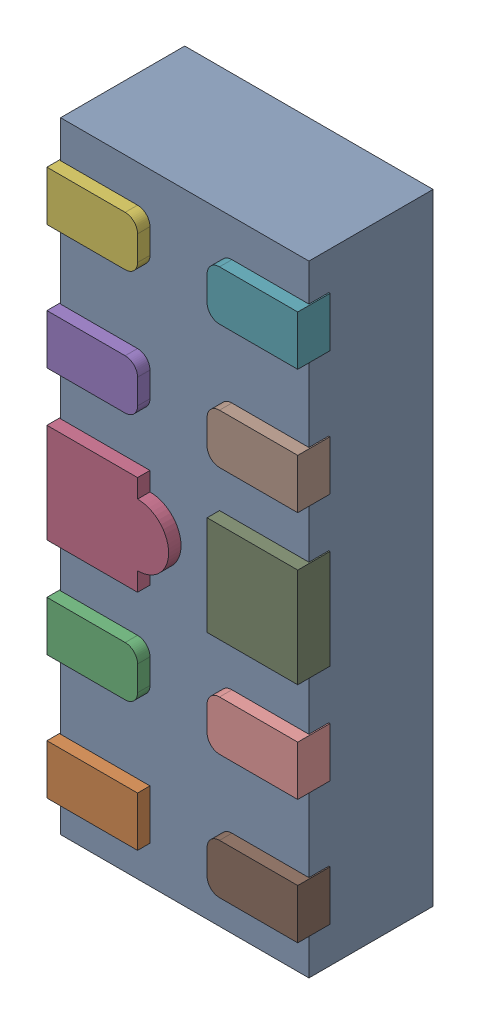
SolidWorks assembly D41, configuration Défaut. Lengths in mm.
Overall size (1.01 2.5 0.55).
12 component instances, 5 part files, 0 mates.
Components (placement in the parent):
- UDFN10-1: UDFN10 [Défaut] at (77.4897 -8.4526 -1.1719) x (0 1 0) z (-1 0 0) size (2.5 0.55 1.01)
  - User Library-UDFN10_Body-1: User Library-UDFN10_Body [Défaut] at (1.0785 0.9721 1.8983) size (2.5 0.5 1)
  - User Library-UDFN10_Pin1-1: User Library-UDFN10_Pin1 [Défaut] at (0.0785 1.0521 2.2208) x (0 0 -1) z (-1 0 0) size (0.37 0.13 0.2)
  - User Library-UDFN10_Pin2-1: User Library-UDFN10_Pin2 [Défaut] at (0.5785 1.0521 2.2208) x (0 0 1) z (1 0 0) size (0.37 0.13 0.2)
  - User Library-UDFN10_Pin4-1: User Library-UDFN10_Pin4 [Défaut] at (1.0785 0.9221 2.2208) x (0 0 1) z (-1 0 0) size (0.49 0.13 0.4)
  - User Library-UDFN10_Pin2-2: User Library-UDFN10_Pin2 [Défaut] at (1.5785 0.9221 2.2208) x (0 0 1) z (-1 0 0) size (0.37 0.13 0.2)
  - User Library-UDFN10_Pin2-3: User Library-UDFN10_Pin2 [Défaut] at (2.0785 0.9221 2.2208) x (0 0 1) z (-1 0 0) size (0.37 0.13 0.2)
  - User Library-UDFN10_Pin2-4: User Library-UDFN10_Pin2 [Défaut] at (2.0785 0.9221 1.5758) x (0 0 -1) z (1 0 0) size (0.37 0.13 0.2)
  - User Library-UDFN10_Pin2-5: User Library-UDFN10_Pin2 [Défaut] at (1.5785 0.9221 1.5758) x (0 0 -1) z (1 0 0) size (0.37 0.13 0.2)
  - User Library-UDFN10_Pin3-1: User Library-UDFN10_Pin3 [Défaut] at (1.0785 0.9221 1.5758) x (0 0 1) z (-1 0 0) size (0.37 0.13 0.4)
  - User Library-UDFN10_Pin2-6: User Library-UDFN10_Pin2 [Défaut] at (0.5785 0.9221 1.5758) x (0 0 -1) z (1 0 0) size (0.37 0.13 0.2)
  - User Library-UDFN10_Pin2-7: User Library-UDFN10_Pin2 [Défaut] at (0.0785 0.9221 1.5758) x (0 0 -1) z (1 0 0) size (0.37 0.13 0.2)
